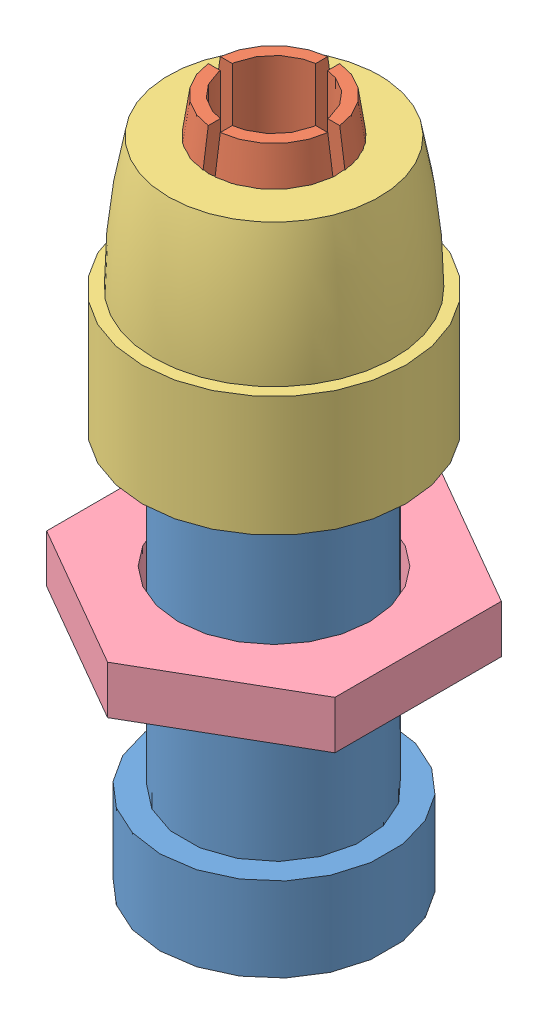
SolidWorks assembly Цанговый зажим, configuration По умолчанию. Lengths in mm.
Overall size (12 28.5 13.86).
4 component instances, 4 part files, 12 mates.
Components (placement in the parent):
- втулка-1: втулка [По умолчанию] at origin size (9.5 23 9.5)
- цанга-1: цанга [По умолчанию] at (0 13 0) size (6 15.5 6)
- прижимная гайка-1: прижимная гайка [По умолчанию] at (0 16.5 0) x (-1 0 0) z (0 0 -1) size (11 10.5 11)
- фиксирующая гайка-1: фиксирующая гайка [По умолчанию] at (0 11.5 0) x (1 0 0) z (0 -1 0) size (12 13.86 2)
Mates (geometry in assembly coordinates):
- Совпадение1: coincident anti-aligned: plane of втулка-1 through (4.75 0 0) normal (0 -1 0); plane of assembly through (0 0 0) normal (0 1 0)
- Совпадение2: coincident aligned: plane of втулка-1 through (0 0 0) normal (0 0 1); plane of assembly through (0 0 0) normal (0 0 1)
- Совпадение3: coincident aligned: plane of втулка-1 through (0 0 0) normal (1 0 0); plane of assembly through (0 0 0) normal (1 0 0)
- Концентричный1: concentric anti-aligned: cylinder of втулка-1 through (0 13 0) axis (0 1 0) radius 3; cylinder of цанга-1 through (0 13 0) axis (0 -1 0) radius 3
- Совпадение4: coincident anti-aligned: plane of втулка-1 through (0 13 0) normal (0 1 0); plane of цанга-1 through (3 13 0) normal (0 -1 0)
- Совпадение5: coincident aligned: plane of цанга-1 through (0 13 0) normal (0 0 1); plane of assembly through (0 0 0) normal (0 0 1)
- Концентричный2: concentric aligned: cylinder of втулка-1 through (0 0 0) axis (0 -1 0) radius 3.75; cylinder of прижимная гайка-1 through (0 20.5 0) axis (0 -1 0) radius 4
- Совпадение6: coincident aligned: cone of цанга-1 through (0 25 0) axis (0 1 0); cone of прижимная гайка-1 through (0 28.5 0) axis (0 1 0)
- Совпадение7: coincident anti-aligned: plane of прижимная гайка-1 through (0 16.5 0) normal (0 0 -1); plane of assembly through (0 0 0) normal (0 0 1)
- Концентричный3: concentric anti-aligned: cylinder of втулка-1 through (0 0 0) axis (0 -1 0) radius 3.75; cylinder of фиксирующая гайка-1 through (0 10.5 0) axis (0 1 0) radius 4
- Совпадение9: coincident aligned: plane of фиксирующая гайка-1; plane of assembly through (0 0 0) normal (1 0 0)
- Coincident1: coincident: plane of фиксирующая гайка-1 through (0 11.5 0) normal (0 1 0); line of assembly
